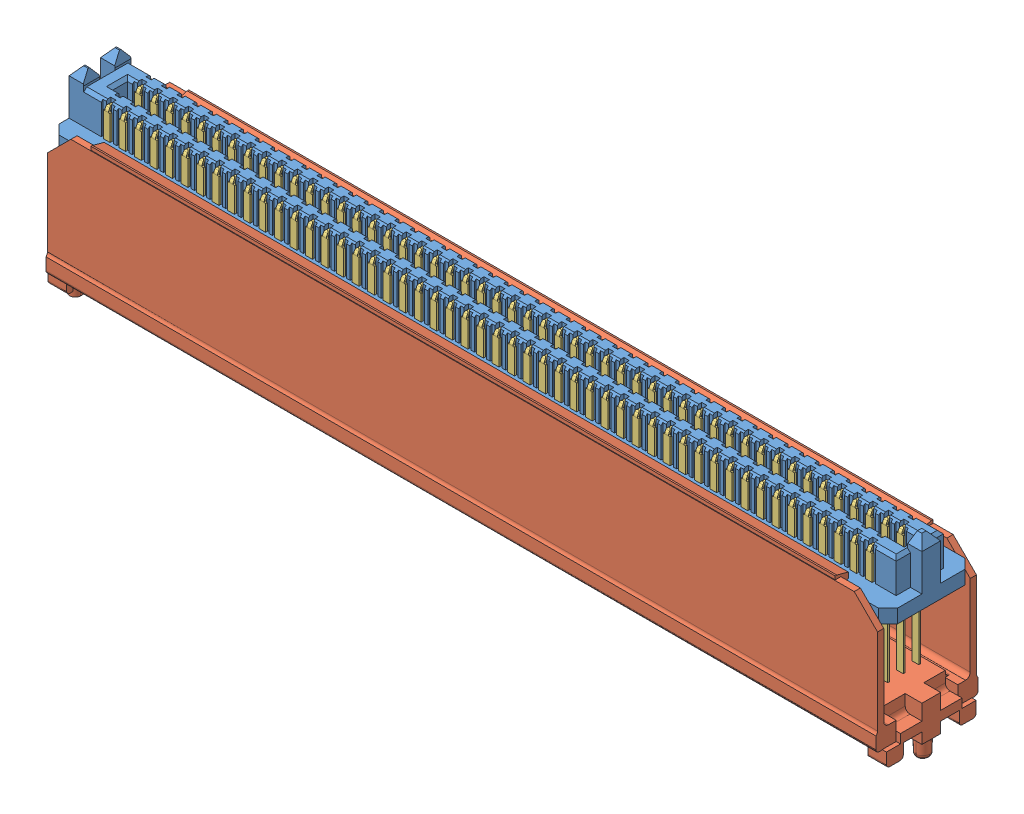
SolidWorks assembly Assem6, configuration Default. Lengths in mm.
Overall size (68.48 15.88 8.33).
6 component instances, 5 part files, 3 mates.
Components (placement in the parent):
- SEAM_50_11_0_L_04_2_A_K_TR-1: SEAM_50_11_0_L_04_2_A_K_TR [Default] at (0 10.8966 0) size (68.48 15.88 8.33)
  - _SEAM_50_11_0_L_04_1_A_K_TR_body_2-1: _SEAM_50_11_0_L_04_1_A_K_TR_body_2 [Default] at origin size (68.48 6.35 7.06)
  - _SEAM_50_11_0_L_04_1_A_K_TR_spacer_4-1: _SEAM_50_11_0_L_04_1_A_K_TR_spacer_4 [Default] at origin size (68.48 13.13 8.33)
  - _SEAM_50_11_0_L_04_1_A_K_TR_conn_6-1: _SEAM_50_11_0_L_04_1_A_K_TR_conn_6 [Default] at origin size (67.97 13.3 6.55)
  - _SEAM_K_Pad_04_8-1: _SEAM_K_Pad_04_8 [Default] at (0 2.6924 0) size (5.99 0.13 5.99) (hidden)
  - _SEAM_Triangle_10-1: _SEAM_Triangle_10 [Default] at (32.2834 1.2954 -1.6764) x (-1 0 0) z (0 0 -1) size (1.02 1.27 0.13)
Mates (geometry in assembly coordinates):
- Coincident1: coincident: plane of ? through (32.7152 0 3.4036) normal (0 -1 0); plane of assembly through (0 0 0) normal (0 1 0)
- Coincident2: coincident: plane of ? through (0 10.8966 0) normal (0 0 1); plane of assembly through (0 0 0) normal (0 0 1)
- Coincident3: coincident: plane of ? through (0 10.8966 0) normal (1 0 0); plane of assembly through (0 0 0) normal (1 0 0)
